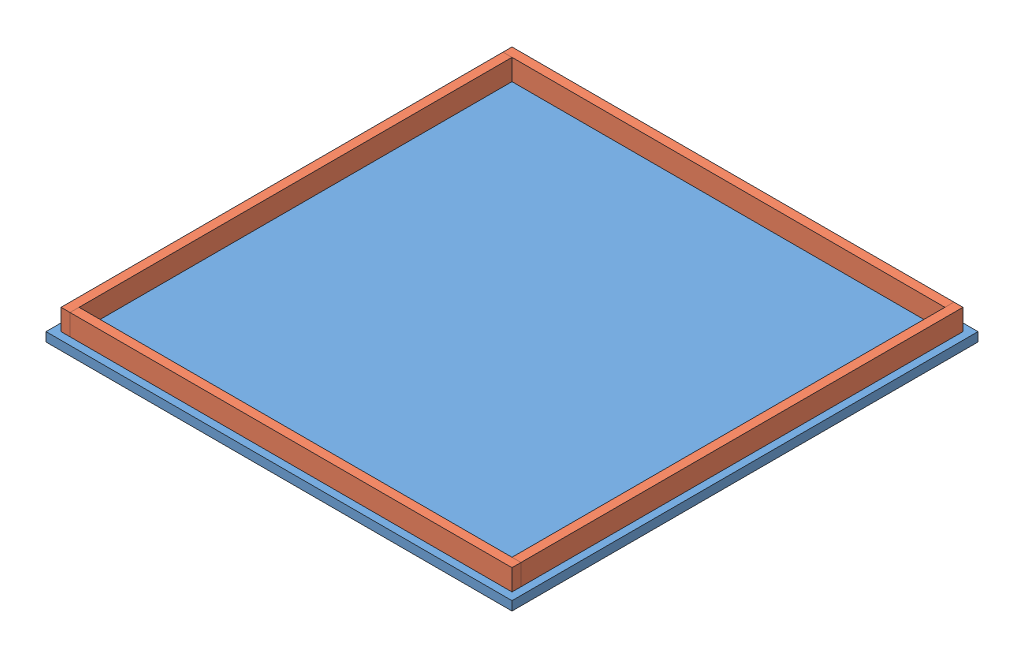
SolidWorks assembly BaseBoxAssly, configuration Default. Lengths in mm.
Overall size (310 20 310).
5 component instances, 2 part files, 12 mates.
Components (placement in the parent):
- BasePlate-1: BasePlate [Default] at (-151.1959 -24.6494 167.7009) size (310 6 310)
- SIdePlate-1: SIdePlate [Default] at (147.8041 -18.6494 9.7009) x (0 0 -1) z (1 0 0) size (294 20 6)
- SIdePlate-2: SIdePlate [Default] at (0.8041 -18.6494 -131.2991) x (-1 0 0) z (0 0 -1) size (294 20 6)
- SIdePlate-3: SIdePlate [Default] at (-140.1959 -18.6494 15.7009) x (0 0 1) z (-1 0 0) size (294 20 6)
- SIdePlate-4: SIdePlate [Default] at (6.8041 -18.6494 156.7009) size (294 20 6)
Mates (geometry in assembly coordinates):
- Distance1: distance aligned: plane of SIdePlate-1 through (153.8041 -18.6494 9.7009) normal (1 0 0); plane of BasePlate-1 through (158.8041 -18.6494 167.7009) normal (1 0 0)
- Coincident5: coincident anti-aligned: plane of BasePlate-1 through (-151.1959 -18.6494 167.7009) normal (0 1 0); plane of SIdePlate-1 through (153.8041 -18.6494 156.7009) normal (0 -1 0)
- Distance2: distance aligned: plane of BasePlate-1 through (-151.1959 -18.6494 167.7009) normal (0 0 1); plane of SIdePlate-1 through (153.8041 -4.6494 156.7009) normal (0 0 1)
- Coincident7: coincident aligned: plane of SIdePlate-1 through (153.8041 -4.6494 -137.2991) normal (0 0 -1); plane of SIdePlate-2 through (0.8041 -18.6494 -137.2991) normal (0 0 -1)
- Coincident8: coincident anti-aligned: plane of BasePlate-1 through (-151.1959 -18.6494 167.7009) normal (0 1 0); plane of SIdePlate-2 through (147.8041 -18.6494 -137.2991) normal (0 -1 0)
- Coincident9: coincident anti-aligned: plane of SIdePlate-1 through (147.8041 -18.6494 9.7009) normal (-1 0 0); plane of SIdePlate-2 through (147.8041 -4.6494 -137.2991) normal (1 0 0)
- Coincident10: coincident aligned: plane of SIdePlate-2 through (-146.1959 -4.6494 -137.2991) normal (-1 0 0); plane of SIdePlate-3 through (-146.1959 -18.6494 15.7009) normal (-1 0 0)
- Coincident11: coincident anti-aligned: plane of BasePlate-1 through (-151.1959 -18.6494 167.7009) normal (0 1 0); plane of SIdePlate-3 through (-146.1959 -18.6494 -131.2991) normal (0 -1 0)
- Coincident12: coincident anti-aligned: plane of SIdePlate-2 through (0.8041 -18.6494 -131.2991) normal (0 0 1); plane of SIdePlate-3 through (-146.1959 -4.6494 -131.2991) normal (0 0 -1)
- Coincident13: coincident aligned: plane of SIdePlate-3 through (-146.1959 -4.6494 162.7009) normal (0 0 1); plane of SIdePlate-4 through (6.8041 -18.6494 162.7009) normal (0 0 1)
- Coincident14: coincident anti-aligned: plane of BasePlate-1 through (-151.1959 -18.6494 167.7009) normal (0 1 0); plane of SIdePlate-4 through (-140.1959 -18.6494 162.7009) normal (0 -1 0)
- Coincident15: coincident anti-aligned: plane of SIdePlate-3 through (-140.1959 -18.6494 15.7009) normal (1 0 0); plane of SIdePlate-4 through (-140.1959 -4.6494 162.7009) normal (-1 0 0)
